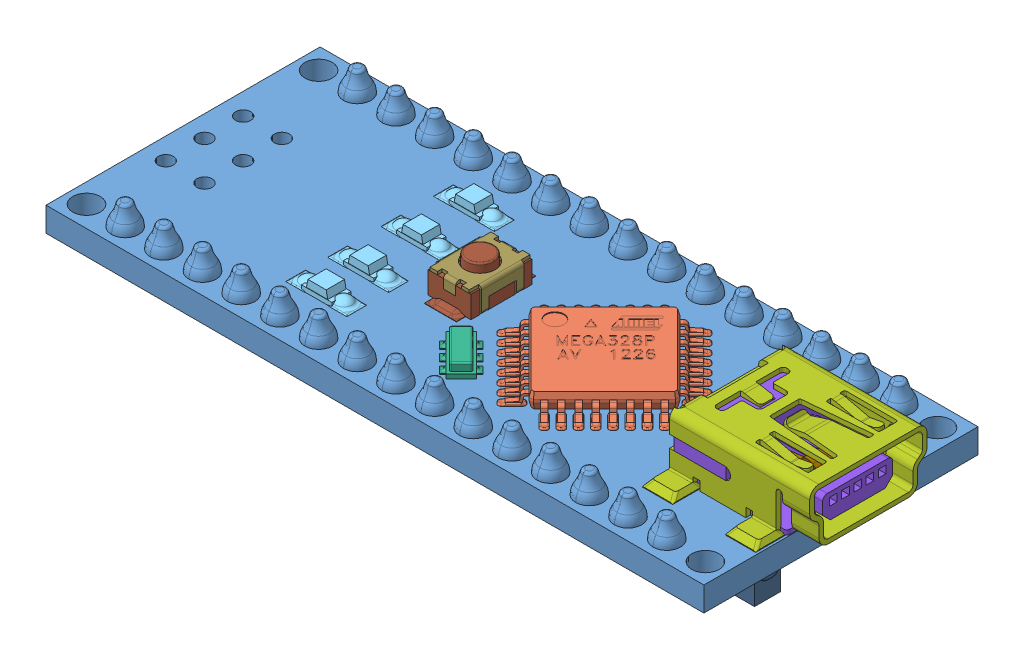
SolidWorks assembly arduino nano part, configuration Default. Lengths in mm.
Overall size (45 7.28 18).
28 component instances, 16 part files, 0 mates.
Components (placement in the parent):
- nano-board-1: nano-board [Default] at origin size (43.2 4.6 18)
- atmega328-1: atmega328 [Default] at (23.85 1.75 -7.62) x (-0.707107 0 0.707107) z (-0.707107 0 -0.707107) size (10 1.11 10)
- ftdi FT232rl-1: ftdi FT232rl [Default] at (29.05 0 -7.67) x (0 0 -1) z (-1 0 0) size (9.25 1.9 10.2)
- smt_resistor222-1: smt_resistor222 [Default] at (21.86 0 -5.8) x (0 0 -1) z (-1 0 0) size (1.7 0.6 3.8)
- smt_resistor222-2: smt_resistor222 [Default] at (21.86 0 -9) x (0 0 -1) z (-1 0 0) size (1.7 0.6 3.8)
- smt_resistor222-3: smt_resistor222 [Default] at (36.75 0 -7.6) x (0 0 -1) z (-1 0 0) size (1.7 0.6 3.8)
- smt_resistor222-4: smt_resistor222 [Default] at (36.75 0 -12) x (0 0 -1) z (-1 0 0) size (1.7 0.6 3.8)
- smt_resistor222-5: smt_resistor222 [Default] at (8.2 0 -2.6) x (0 0 -1) z (-1 0 0) size (1.7 0.6 3.8)
- led-1: led [Default] at (10.4 1.6 -2.8) size (4 0.9 1.55)
- led-2: led [Default] at (10.4 1.6 -5.55) size (4 0.9 1.55)
- led-3: led [Default] at (10.4 1.6 -12.5) size (4 0.9 1.55)
- led-4: led [Default] at (10.4 1.6 -9.05) size (4 0.9 1.55)
- 16mhz crystal - measured-1: 16mhz crystal - measured [Default] at (18.5113 1.6 -3.5541) x (0.707107 0 0.707107) z (-0.707107 0 0.707107) size (3.4 0.8 2)
- MINIUSBSHELL-1: MINIUSBSHELL [Default] at (38.98 1.65 -7.62) x (0 0 1) z (-1 0 0) size (10.9 3.85 9.41)
- MINIUSBCORE-1: MINIUSBCORE [Default] at (32.28 1.65 -7.62) x (0 0 -1) z (1 0 0) size (7.7 4.5 8.2)
- MINI USB CONTACT-1: MINI USB CONTACT [Default] at (33.28 1.65 -9.22) x (0 0 -1) z (1 0 0) size (0.53 2.55 9.41)
- MINI USB CONTACT-2: MINI USB CONTACT [Default] at (33.28 1.65 -8.42) x (0 0 -1) z (1 0 0) size (0.53 2.55 9.41)
- MINI USB CONTACT-3: MINI USB CONTACT [Default] at (33.28 1.65 -7.62) x (0 0 -1) z (1 0 0) size (0.53 2.55 9.41)
- MINI USB CONTACT-4: MINI USB CONTACT [Default] at (33.28 1.65 -6.82) x (0 0 -1) z (1 0 0) size (0.53 2.55 9.41)
- MINI USB CONTACT-5: MINI USB CONTACT [Default] at (33.28 1.65 -6.02) x (0 0 -1) z (1 0 0) size (0.53 2.55 9.41)
- cap106C-1: cap106C [Default] at (37.2 0 -3.3) x (0 0 1) z (1 0 0) size (1.7 1.81 4)
- cap106C-2: cap106C [Default] at (7.9 0 -5.6) x (0 0 -1) z (-1 0 0) size (1.7 1.81 4)
- reset core-1: reset core [Default] at (15.25 1.6 -8.05) x (0 0 -1) z (1 0 0) size (5.2 2.15 2.8)
- reset shell-1: reset shell [Default] at (15.25 3.25 -8.05) size (3 1.65 4)
- nano - reg-1: nano - reg [Default] at (6.1 0 -10.16) x (0 0 -1) z (-1 0 0) size (6.5 1.69 8.3)
- NANO DIODE-1: NANO DIODE [Default] at (11.43 0 -4.2) x (0 0 1) z (1 0 0) size (4.92 1.38 1.7)
- 189 RESISTOR PACK-1: 189 RESISTOR PACK [Default] at (15.75 0 -10.85) x (0 0 1) z (1 0 0) size (3.2 0.51 3)
- 102 RESISTOR PACK-1: 102 RESISTOR PACK [Default] at (15.75 0 -5.2) x (0 0 1) z (1 0 0) size (3.2 0.51 3)
